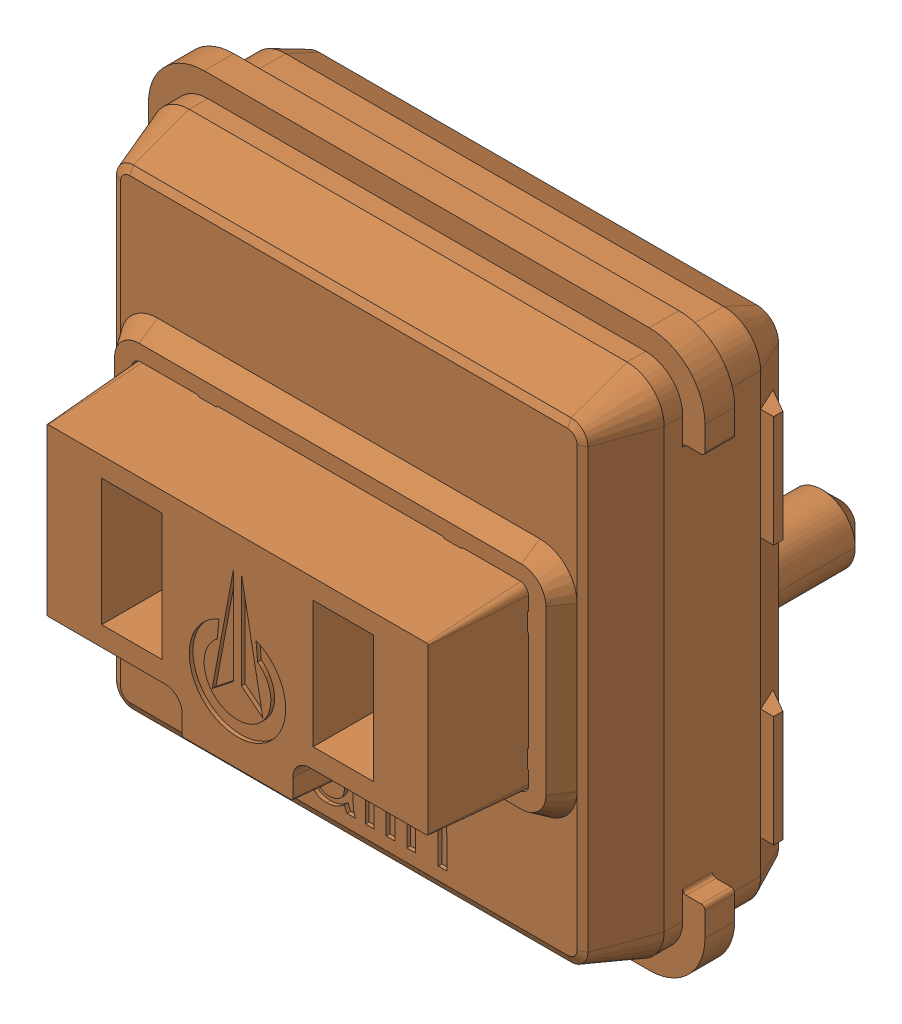
SolidWorks assembly SW2_1.step, configuration Default. Lengths in mm.
Overall size (15 15 11.1).
2 component instances, 2 part files, 0 mates.
Components (placement in the parent):
- WS2812-2020_1.step-3: WS2812-2020_1.step [Default] at (517.4468 231.0345 0.3) x (1 0 0) z (0 -1 0) size (2.2 0.86 2)
- Kailh LP Choc Burnt Orange_1.step-3: Kailh LP Choc Burnt Orange_1.step [Default] at (517.3402 226.3933 2.7) x (0 -1 0) z (-1 0 0) size (15 11.1 15)
